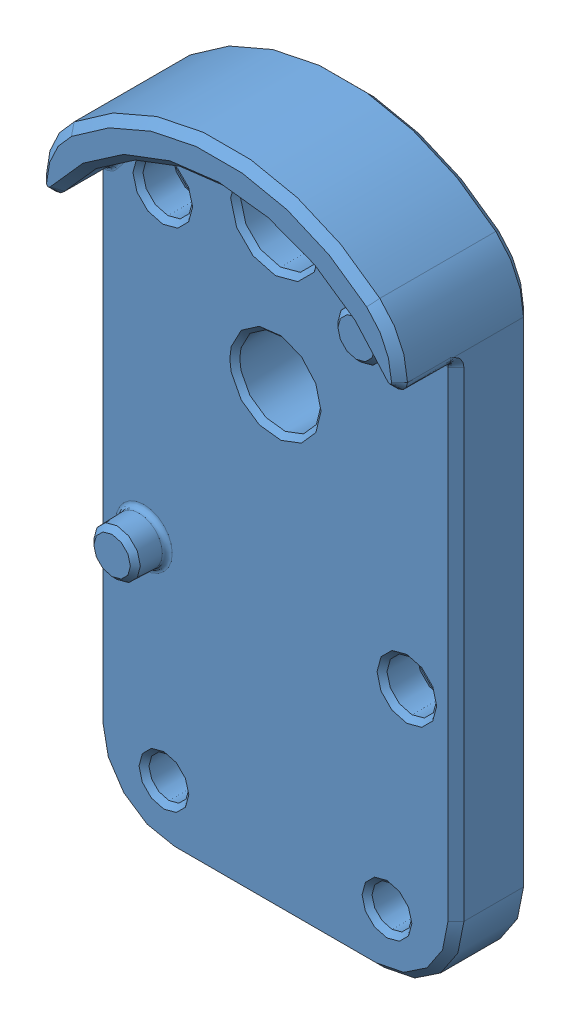
SolidWorks assembly AARL_Puppy_18_01_04_SlabAssembly2, configuration Default. Lengths in mm.
Overall size (29.26 55.03 13.69).
2 component instances, 1 part files, 3 mates.
Components (placement in the parent):
- AARL_Puppy_18_01_04_043-1: AARL_Puppy_18_01_04_043 [Default] at (25.7495 36.0819 36.9303) size (29.26 55.03 13.69)
- CUI_DEVICES_cui_devices_amt102-0048-i6350-s-1: CUI_DEVICES_cui_devices_amt102-0048-i6350-s [Default] at (25.7495 36.0819 46.7201) (suppressed, hidden)
Mates (geometry in assembly coordinates):
- Concentric1: concentric anti-aligned: cylinder of AARL_Puppy_18_01_04_043-1 through (25.7495 36.0819 42.9501) axis (0 0 -1) radius 3.2385; cylinder of CUI_DEVICES_cui_devices_amt102-0048-i6350-s-1/CUI_DEVICES_amt-sleeve-rev-d(d)-1 through (25.7495 36.0819 44.3001) axis (0 0 1) radius 3.175
- Coincident1: coincident anti-aligned: plane of AARL_Puppy_18_01_04_043-1 through (25.7495 35.9295 42.9501) normal (0 0 1); plane of CUI_DEVICES_cui_devices_amt102-0048-i6350-s-1/CUI_DEVICES_amt-102-base-rev-k-1 through (25.7495 25.6619 42.9501) normal (0 0 -1)
- Concentric2: concentric aligned: cylinder of AARL_Puppy_18_01_04_043-1 through (36.227 20.3339 36.9303) axis (0 0 1) radius 1.9812; cylinder of CUI_DEVICES_cui_devices_amt102-0048-i6350-s-1/CUI_DEVICES_amt-102-base-rev-k-1 through (36.227 20.3339 42.9501) axis (0 0 1) radius 1.9812
